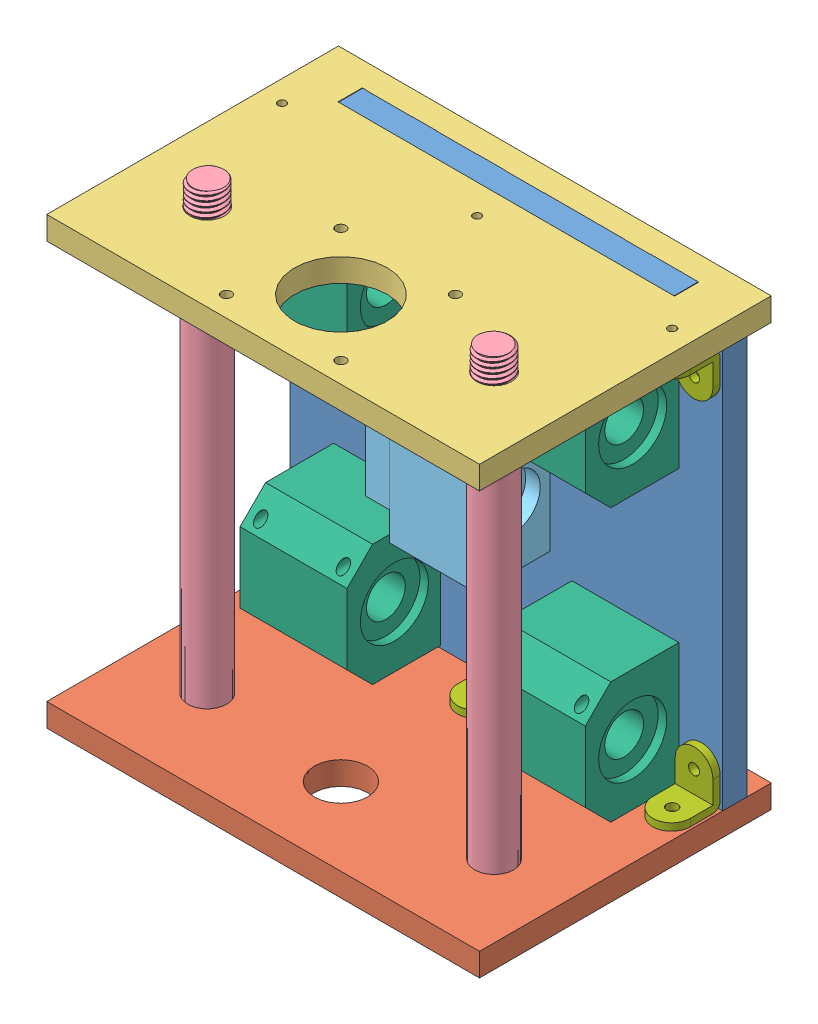
SolidWorks assembly Z frame, configuration Default. Lengths in mm.
Overall size (178 203.39 120).
16 component instances, 7 part files, 22 mates.
Components (placement in the parent):
- X sliding panel-1: X sliding panel [Default] at (74.0708 130.421 77.6344) x (1 0 0) z (0 0 -1) size (178 183 10)
- Z bottom panel-1: Z bottom panel [Default] at (74.0708 38.921 117.6344) size (178 9.5 120)
- Z top panel-1: Z top panel [Default] at (74.0708 212.421 117.6344) size (178 9.5 120)
- Z rod-1: Z rod [Default] at (15.0708 98.4439 141.6344) x (0.598405 0 0.801194) z (0 -1 0) size (16 16 203.39)
- Z rod-3: Z rod [Default] at (133.0708 98.4439 141.6344) x (1 0 0) z (0 -1 0) size (16 16 203.39)
- screw block-2: screw block [Default] at (92.0708 130.421 92.6344) x (0 1 0) z (-1 0 0) size (50 30 47.5)
- sliding block-5: sliding block [Default] at (123.0708 74.421 116.1344) x (0 -1 0) z (0 0 -1) size (50 44 38.5)
- sliding block-6: sliding block [Default] at (123.0708 186.421 116.1344) x (0 -1 0) z (0 0 -1) size (50 44 38.5)
- sliding block-7: sliding block [Default] at (25.0708 186.421 116.1344) x (0 -1 0) z (0 0 -1) size (50 44 38.5)
- sliding block-8: sliding block [Default] at (25.0708 74.421 116.1344) x (0 -1 0) z (0 0 -1) size (50 44 38.5)
- corner connector #20-1: corner connector #20 [Default] at (-6.1792 54.546 77.6344) size (15.5 20 20)
- corner connector #20-2: corner connector #20 [Default] at (74.0708 54.546 77.6344) size (15.5 20 20)
- corner connector #20-3: corner connector #20 [Default] at (154.3208 54.546 77.6344) size (15.5 20 20)
- corner connector #20-4: corner connector #20 [Default] at (154.3208 206.296 77.6344) x (-1 0 0) z (0 0 1) size (15.5 20 20)
- corner connector #20-5: corner connector #20 [Default] at (74.0708 206.296 77.6344) x (-1 0 0) z (0 0 1) size (15.5 20 20)
- corner connector #20-6: corner connector #20 [Default] at (-6.1792 206.296 77.6344) x (-1 0 0) z (0 0 1) size (15.5 20 20)
Mates (geometry in assembly coordinates):
- ProfileCenter1: profile center = 0 mm aligned: circle of screw block-2; circle of X sliding panel-1
- Concentric1: concentric anti-aligned: cylinder of X sliding panel-1 through (62.0708 112.921 67.6344) axis (0 0 1) radius 2.6; cylinder of screw block-2 through (62.0708 112.921 77.6344) axis (0 0 -1) radius 2.1
- ProfileCenter2: profile center = 0 mm aligned: circle of sliding block-6; circle of X sliding panel-1
- Concentric2: concentric anti-aligned: cylinder of X sliding panel-1 through (106.0708 168.421 67.6344) axis (0 0 1) radius 2.6; cylinder of sliding block-6 through (106.0708 168.421 77.6344) axis (0 0 -1) radius 2.1
- ProfileCenter3: profile center = 0 mm aligned: circle of sliding block-7; circle of X sliding panel-1
- Concentric3: concentric anti-aligned: cylinder of X sliding panel-1 through (42.0708 204.421 67.6344) axis (0 0 1) radius 2.6; cylinder of sliding block-7 through (42.0708 204.421 77.6344) axis (0 0 -1) radius 2.1
- ProfileCenter4: profile center = 0 mm aligned: circle of sliding block-8; circle of X sliding panel-1
- Concentric4: concentric anti-aligned: cylinder of X sliding panel-1 through (42.0708 56.421 67.6344) axis (0 0 1) radius 2.6; cylinder of sliding block-8 through (42.0708 56.421 77.6344) axis (0 0 -1) radius 2.1
- ProfileCenter5: profile center = 0 mm aligned: circle of sliding block-5; circle of X sliding panel-1
- Concentric5: concentric anti-aligned: cylinder of X sliding panel-1 through (140.0708 56.421 67.6344) axis (0 0 1) radius 2.6; cylinder of sliding block-5 through (140.0708 56.421 77.6344) axis (0 0 -1) radius 2.1
- ProfileCenter6: profile center = 0 mm anti-aligned: circle of corner connector #20-3; circle of X sliding panel-1
- ProfileCenter7: profile center = 0 mm anti-aligned: circle of corner connector #20-2; circle of X sliding panel-1
- ProfileCenter8: profile center = 0 mm anti-aligned: circle of corner connector #20-1; circle of X sliding panel-1
- ProfileCenter9: profile center = 0 mm anti-aligned: circle of corner connector #20-4; circle of X sliding panel-1
- ProfileCenter10: profile center = 0 mm anti-aligned: circle of corner connector #20-5; circle of X sliding panel-1
- ProfileCenter11: profile center = 0 mm anti-aligned: circle of X sliding panel-1; circle of corner connector #20-6
- ProfileCenter13: profile center = 0 mm aligned: circle of Z top panel-1; circle of corner connector #20-4
- Concentric12: concentric anti-aligned: cylinder of Z top panel-1 through (-6.1792 221.921 89.6344) axis (0 1 0) radius 1.65; cylinder of corner connector #20-6 through (-6.1792 212.421 89.6344) axis (0 -1 0) radius 2.25
- ProfileCenter14: profile center = 0 mm anti-aligned: circle of corner connector #20-1; circle of Z bottom panel-1
- Concentric13: concentric aligned: cylinder of Z bottom panel-1 through (74.0708 48.421 89.6344) axis (0 1 0) radius 1.65; cylinder of corner connector #20-2 through (74.0708 48.421 89.6344) axis (0 1 0) radius 2.25
- ProfileCenter17: profile center = 0 mm anti-aligned: circle of Z rod-1; circle of Z top panel-1
- ProfileCenter18: profile center = 0 mm anti-aligned: circle of Z rod-3; circle of Z top panel-1
